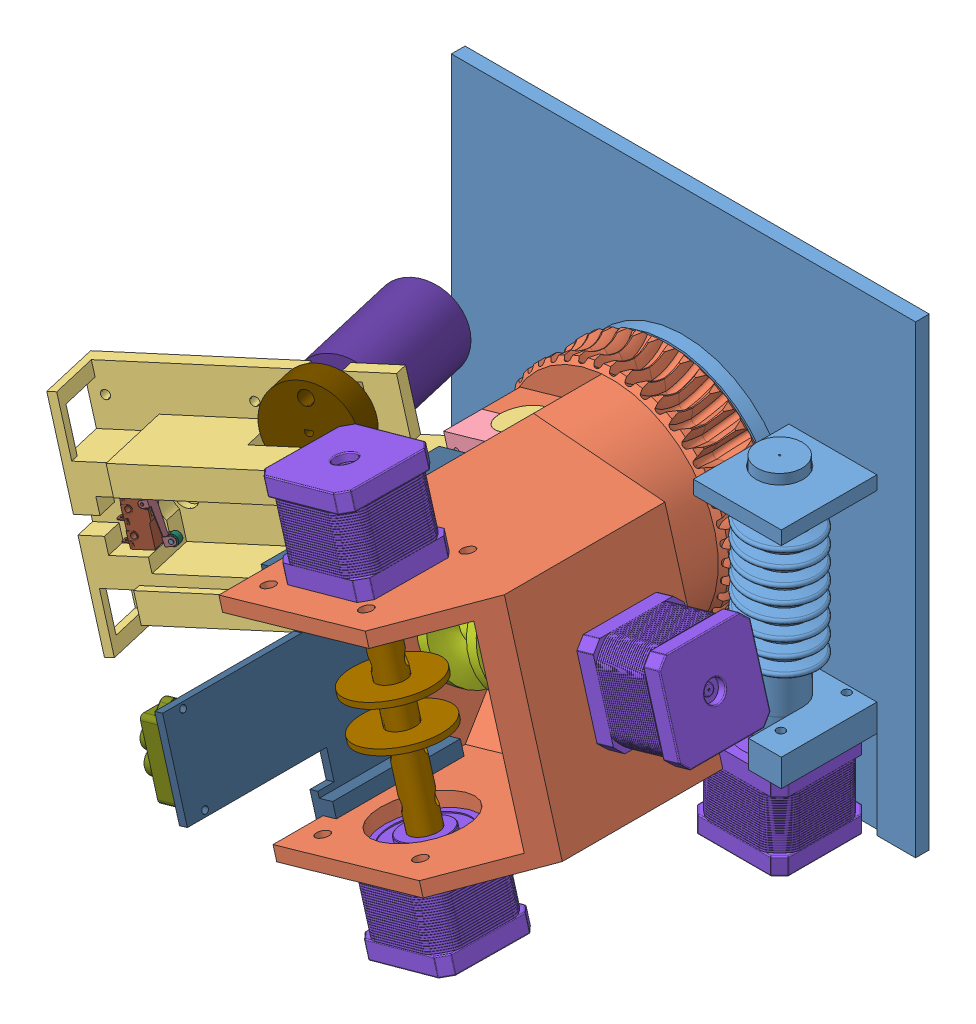
SolidWorks assembly AssemV5, configuration Default. Lengths in mm.
Overall size (330.56 216.84 251.9).
26 component instances, 19 part files, 48 mates.
Components (placement in the parent):
- StaticBaseV-2: StaticBaseV [Default] at (-73.3516 -55.0202 184.3743) size (215.9 215.9 50.8)
- EE183 - BaseV8-1: EE183 - BaseV8 [Varsayılan] at (34.5984 50.9073 210.6943) x (-0.27522 0.961381 0) z (0 0 -1) size (107.89 159.94 205.32)
- LaunchRailV9-1: LaunchRailV9 [Default] at (27.5196 31.2188 237.3254) x (-0.27522 0.961381 0) z (0.918082 0.262825 -0.29673) size (97.46 43.1 180.34)
- EE183B - RailConstraintV1-1: EE183B - RailConstraintV1 [Default] at (12.0372 6.9713 242.0943) x (0.961381 0.27522 0) z (-0.27522 0.961381 0) size (38.1 17.78 12.7)
- EE183B - RailConstraintV1-2: EE183B - RailConstraintV1 [Default] at (-4.2998 64.0387 242.0943) x (0.961381 0.27522 0) z (-0.27522 0.961381 0) size (38.1 17.78 12.7)
- EE183 - LaunchCartV5-1: EE183 - LaunchCartV5 [Default] at (3.8179 24.4336 248.0979) x (0.27522 -0.961381 0) z (-0.285271 -0.081666 -0.954961) size (45.72 40.64 34.29)
- EE183 - SolenoidV1-1: EE183 - SolenoidV1 [Default] at (32.5105 35.818 235.4411) x (-0.918082 -0.262825 0.29673) z (-0.27522 0.961381 0) size (54.73 25 26.63)
- EE183 - AugarV3-1: EE183 - AugarV3 [Default] at (252.3237 113.2278 316.3785) x (-0.114553 0.400148 -0.909263) z (0.961381 0.27522 0) size (38.1 38.1 90.17)
- Motor a Pasos Nema 17-1: Motor a Pasos Nema 17 [Predeterminado] at (52.3182 148.4565 366.0543) x (0.011317 0.00324 -0.999931) z (-0.961315 -0.275201 -0.011772) size (42.3 64.2 42.3)
- Motor a Pasos Nema 17-2: Motor a Pasos Nema 17 [Predeterminado] at (174.9581 91.0889 316.3893) x (-0.27522 0.961381 0) z (0 0 1) size (42.3 64.2 42.3)
- Motor a Pasos Nema 17-3: Motor a Pasos Nema 17 [Predeterminado] at (101.2552 -22.487 366.0543) x (0.961277 0.27519 0.014751) z (-0.014181 -0.00406 0.999891) size (42.3 64.2 42.3)
- EE183 - WindWheelV4-1: EE183 - WindWheelV4 [Default] at (90.246 15.9697 366.0543) x (0.694336 0.198772 0.691655) z (-0.27522 0.961381 0) size (38.1 38.1 95.81)
- EE183DB - SensorHolderV3-1: EE183DB - SensorHolderV3 [Default] at (17.9642 97.015 319.5643) x (0 0 -1) z (0.27522 -0.961381 0) size (148.46 25.62 97.79)
- Limit Switch-1: Limit Switch [Default] at (-126.03 11.7882 285.2276) x (0.27522 -0.961381 0) z (0.285271 0.081666 0.954961) size (19.88 22.22 6.9)
  - Body-1: Body [Default] at (-3.0926 15.7185 13.5391) size (19.88 14.3 6.9)
  - Switch_Button-1: Switch_Button [Default] at (3.7604 12.3412 16.7891) size (2 4 4)
  - Link-1: Link [Default] at (-1.7251 15.5431 16.7891) x (0.988221 0.153035 0) z (0 0 1) size (18.04 8.82 6.05)
  - Wheel shaft-1: Wheel shaft [Default] at (13.789 21.2849 14.2391) x (-0.16928 0.985568 0) z (0 0 1) size (1.82 1.82 5.1)
  - Wheel-1: Wheel [Default] at (13.789 21.2849 15.2941) x (0.999957 0.009288 0) z (0 0 1) size (4.67 4.67 2.99)
- mini_Lidar-1: mini_Lidar [Défaut] at (39.8186 52.9761 427.3873) x (0.27522 -0.961381 0) z (-0.961381 -0.27522 0) size (41.76 15 16)
- EE183 - MotorV2-1: EE183 - MotorV2 [Default] at (-40.447 -5.4116 262.0911) x (-0.936617 -0.187685 0.295842) z (-0.285271 -0.081666 -0.954961) size (36.6 36.6 64.52)
- EE183 - MotorV2-2: EE183 - MotorV2 [Default] at (-58.8812 58.9815 262.0911) x (-0.936617 -0.187685 0.295842) z (-0.285271 -0.081666 -0.954961) size (36.6 36.6 64.52)
- EE183 - WheelV1-1: EE183 - WheelV1 [Default] at (-54.896 60.1224 275.4319) x (-0.946187 -0.134858 0.294183) z (-0.285271 -0.081666 -0.954961) size (38.1 38.1 19.05)
- EE183 - WheelV1-2: EE183 - WheelV1 [Default] at (-36.4618 -4.2707 275.4319) x (-0.720576 0.675249 0.157508) z (-0.285271 -0.081666 -0.954961) size (38.1 38.1 19.05)
- EE183 - WormGearV2-1: EE183 - WormGearV2 [Varsayılan] at (91.0536 52.0794 204.9983) x (0 1 0) z (-0.546944 0 0.837169) size (108.6 34.9 36.7)
- Motor a Pasos Nema 17-4: Motor a Pasos Nema 17 [Predeterminado] at (98.3792 -55.9586 209.7858) size (42.3 64.2 42.3)
Mates (geometry in assembly coordinates):
- Concentric2: concentric: circle of StaticBaseV-2; cylinder of EE183 - BaseV8-1 through (34.5984 50.9073 209.7743) axis (0 0 -1) radius 38.862
- Coincident2: coincident: plane of StaticBaseV-2 through (-73.3516 -55.0202 209.7743) normal (0 0 1); plane of EE183 - BaseV8-1 through (34.5984 50.9073 209.7743) normal (0 0 -1)
- Concentric3: concentric: cylinder of EE183 - BaseV8-1 through (35.2819 -5.0083 242.0943) axis (-0.27522 0.961381 0) radius 10.16; cylinder of LaunchRailV9-1 through (30.3515 12.2143 242.0943) axis (-0.27522 0.961381 0) radius 10.16
- Coincident3: coincident: plane of EE183 - BaseV8-1 through (-7.7951 76.2482 242.0943) normal (-0.27522 0.961381 0); circle of LaunchRailV9-1
- Concentric4: concentric: cylinder of EE183 - BaseV8-1 through (-1.7741 71.3668 197.0743) axis (0 0 1) radius 1.143; cylinder of EE183B - RailConstraintV1-2 through (-1.7741 71.3668 259.8743) axis (0 0 -1) radius 1.143
- Coincident4: coincident: cylinder of EE183 - BaseV8-1 through (26.3078 79.406 197.0743) axis (0 0 1) radius 1.143; circle of EE183B - RailConstraintV1-2
- Coincident5: coincident: plane of EE183 - BaseV8-1 through (34.5984 50.9073 242.0943) normal (0 0 1); plane of EE183B - RailConstraintV1-2 through (-7.7951 76.2482 242.0943) normal (0 0 -1)
- Concentric5: concentric: cylinder of EE183 - BaseV8-1 through (42.6448 22.3386 197.0743) axis (0 0 1) radius 1.143; cylinder of EE183B - RailConstraintV1-1 through (42.6448 22.3386 259.8743) axis (0 0 -1) radius 1.143
- Concentric6: concentric: cylinder of EE183 - BaseV8-1 through (14.5629 14.2994 197.0743) axis (0 0 1) radius 1.143; cylinder of EE183B - RailConstraintV1-1 through (14.5629 14.2994 259.8743) axis (0 0 -1) radius 1.143
- Coincident6: coincident: plane of EE183 - BaseV8-1 through (34.5984 50.9073 242.0943) normal (0 0 1); plane of EE183B - RailConstraintV1-1 through (8.5419 19.1808 242.0943) normal (0 0 -1)
- Coincident10: coincident: plane of LaunchRailV9-1 through (-161.5192 12.4255 320.5914) normal (0.285271 0.081666 0.954961); plane of EE183 - LaunchCartV5-1 through (-27.4788 15.4741 280.2895) normal (-0.285271 -0.081666 -0.954961)
- Coincident11: coincident: plane of LaunchRailV9-1 through (-161.5192 12.4255 320.5914) normal (0.285271 0.081666 0.954961); plane of EE183 - LaunchCartV5-1 through (-27.4788 15.4741 280.2895) normal (-0.285271 -0.081666 -0.954961)
- Coincident12: coincident: plane of LaunchRailV9-1 through (-159.0347 -22.1872 297.621) normal (-0.27522 0.961381 0); plane of EE183 - LaunchCartV5-1 through (-33.4929 13.7524 260.157) normal (0.27522 -0.961381 0)
- Coincident13: coincident: plane of LaunchRailV9-1 through (38.3343 41.4086 258.4116) normal (-0.918082 -0.262825 0.29673); plane of EE183 - SolenoidV1-1 through (25.1809 61.4214 235.4411) normal (0.918082 0.262825 -0.29673)
- Coincident14: coincident: plane of LaunchRailV9-1 through (-159.0347 -22.1872 297.621) normal (0.285271 0.081666 0.954961); plane of EE183 - SolenoidV1-1 through (25.1809 61.4214 235.4411) normal (-0.285271 -0.081666 -0.954961)
- Coincident15: coincident: plane of LaunchRailV9-1 through (11.8822 57.6143 212.3228) normal (0.27522 -0.961381 0); plane of EE183 - SolenoidV1-1 through (25.1809 61.4214 235.4411) normal (-0.27522 0.961381 0)
- Coincident16: coincident: plane of EE183 - LaunchCartV5-1 through (3.8179 24.4336 248.0979) normal (0.918082 0.262825 -0.29673); circle of EE183 - SolenoidV1-1
- Concentric7: concentric: cylinder of EE183 - BaseV8-1 through (-17.2626 36.0607 316.3893) axis (0.961381 0.27522 0) radius 17; cylinder of Motor a Pasos Nema 17-2 through (113.2375 73.4197 316.3893) axis (0.961381 0.27522 0) radius 2.5
- Coincident17: coincident: plane of EE183 - BaseV8-1 through (136.5029 80.0801 344.9643) normal (0.961381 0.27522 0); plane of Motor a Pasos Nema 17-2 through (136.5029 80.0801 316.3893) normal (-0.961381 -0.27522 0)
- Concentric8: concentric: cylinder of EE183 - AugarV3-1 through (201.7326 98.7538 316.3893) axis (-0.961381 -0.27522 0) radius 4.7625; cylinder of Motor a Pasos Nema 17-2 through (113.2375 73.4197 316.3893) axis (0.961381 0.27522 0) radius 2.5
- Coincident18: coincident: plane of EE183 - AugarV3-1 through (134.3142 80.4587 317.4416) normal (0.961381 0.27522 0); plane of Motor a Pasos Nema 17-2 through (134.5801 79.5296 316.3893) normal (-0.961381 -0.27522 0)
- Concentric9: concentric: cylinder of EE183 - BaseV8-1 through (61.9402 114.8457 366.0543) axis (0.27522 -0.961381 0) radius 20; cylinder of Motor a Pasos Nema 17-1 through (69.9873 86.7359 366.0543) axis (-0.27522 0.961381 0) radius 2.5
- Coincident19: coincident: plane of EE183 - BaseV8-1 through (21.1387 97.9238 344.9643) normal (-0.27522 0.961381 0); plane of Motor a Pasos Nema 17-1 through (63.327 110.0013 366.0543) normal (0.27522 -0.961381 0)
- Concentric10: concentric: cylinder of EE183 - BaseV8-1 through (61.9402 114.8457 366.0543) axis (0.27522 -0.961381 0) radius 20; cylinder of Motor a Pasos Nema 17-3 through (83.5861 39.2337 366.0543) axis (0.27522 -0.961381 0) radius 2.5
- Coincident20: coincident: plane of EE183 - BaseV8-1 through (48.0581 3.8907 344.9643) normal (0.27522 -0.961381 0); plane of Motor a Pasos Nema 17-3 through (90.2464 15.9682 366.0543) normal (-0.27522 0.961381 0)
- Concentric11: concentric: cylinder of Motor a Pasos Nema 17-1 through (69.9873 86.7359 366.0543) axis (-0.27522 0.961381 0) radius 2.5; cylinder of EE183 - WindWheelV4-1 through (63.8774 108.0785 366.0543) axis (0.27522 -0.961381 0) radius 6.35
- Coincident21: coincident: plane of Motor a Pasos Nema 17-1 through (63.8774 108.0785 366.0543) normal (0.27522 -0.961381 0); plane of EE183 - WindWheelV4-1 through (63.8774 108.0785 366.0543) normal (-0.27522 0.961381 0)
- Coincident22: coincident: plane of EE183 - BaseV8-1 through (34.5984 50.9073 344.9643) normal (0 0 1); plane of EE183DB - SensorHolderV3-1 through (66.0094 22.2611 344.9643) normal (0 0 -1)
- Coincident23: coincident: plane of EE183 - BaseV8-1 through (43.6335 53.4938 287.8143) normal (-0.961381 -0.27522 0); plane of EE183DB - SensorHolderV3-1 through (31.9214 94.4055 319.5643) normal (0.961381 0.27522 0)
- Coincident24: coincident: plane of EE183 - BaseV8-1 through (21.1387 97.9238 344.9643) normal (-0.27522 0.961381 0); plane of EE183DB - SensorHolderV3-1 through (17.9642 97.015 319.5643) normal (-0.27522 0.961381 0)
- Concentric12: concentric: cylinder of LaunchRailV9-1 through (-120.0759 11.4098 276.4604) axis (0.285271 0.081666 0.954961) radius 1.143; cylinder of Limit Switch-1/Body-1 through (-115.2994 12.7772 292.45) axis (0.285271 0.081666 0.954961) radius 1.225
- Coincident25: coincident: plane of LaunchRailV9-1 through (-110.2016 20.5114 293.9309) normal (0.285271 0.081666 0.954961); plane of Limit Switch-1/Body-1 through (-104.1816 0.9971 293.8014) normal (-0.285271 -0.081666 -0.954961)
- Parallel2: parallel: plane of LaunchRailV9-1 through (-101.3612 0.5849 303.6333) normal (-0.27522 0.961381 0); line of Limit Switch-1/Body-1 through (-110.4891 -1.2246 302.6821) axis (0.918082 0.262825 -0.29673)
- Concentric15: concentric: circle of EE183DB - SensorHolderV3-1; cylinder of mini_Lidar-1 through (30.0578 68.9048 427.3873) axis (0.961381 0.27522 0) radius 0.5875
- Parallel3: parallel: plane of EE183DB - SensorHolderV3-1 through (17.9642 97.015 436.2773) normal (0 0 1); plane of mini_Lidar-1 through (25.2528 63.8887 434.8873) normal (0 0 1)
- Coincident28: coincident: plane of EE183DB - SensorHolderV3-1 through (27.5595 95.7989 294.1643) normal (-0.961381 -0.27522 0); plane of mini_Lidar-1 through (35.8279 66.9161 421.8873) normal (0.961381 0.27522 0)
- Concentric16: concentric: cylinder of LaunchRailV9-1 through (-67.2033 56.5991 234.2324) axis (0.285271 0.081666 0.954961) radius 7.62; cylinder of EE183 - MotorV2-2 through (-77.2869 53.7124 200.477) axis (0.285271 0.081666 0.954961) radius 18.3
- Coincident29: coincident: plane of LaunchRailV9-1 through (-171.9402 16.0473 291.5569) normal (-0.285271 -0.081666 -0.954961); plane of EE183 - MotorV2-2 through (-61.055 58.3592 254.8143) normal (0.285271 0.081666 0.954961)
- Concentric17: concentric: cylinder of LaunchRailV9-1 through (-48.7691 -7.794 234.2324) axis (0.285271 0.081666 0.954961) radius 7.62; cylinder of EE183 - MotorV2-1 through (-58.8527 -10.6807 200.477) axis (0.285271 0.081666 0.954961) radius 18.3
- Coincident30: coincident: plane of LaunchRailV9-1 through (-171.9402 16.0473 291.5569) normal (-0.285271 -0.081666 -0.954961); plane of EE183 - MotorV2-1 through (-42.6208 -6.0339 254.8143) normal (0.285271 0.081666 0.954961)
- Concentric18: concentric: cylinder of EE183 - MotorV2-2 through (-61.055 58.3592 254.8143) axis (0.285271 0.081666 0.954961) radius 1.5875; cylinder of EE183 - WheelV1-1 through (-60.3304 58.5666 257.2399) axis (0.285271 0.081666 0.954961) radius 6.35
- Distance1: distance = 2.54 mm: plane of EE183 - WheelV1-1 through (-60.3304 58.5666 257.2399) normal (-0.285271 -0.081666 -0.954961); plane of EE183 - MotorV2-2 through (-61.055 58.3592 254.8143) normal (0.285271 0.081666 0.954961)
- Concentric19: concentric: cylinder of EE183 - MotorV2-1 through (-58.8527 -10.6807 200.477) axis (0.285271 0.081666 0.954961) radius 18.3; cylinder of EE183 - WheelV1-2 through (-41.8962 -5.8265 257.2399) axis (0.285271 0.081666 0.954961) radius 6.35
- Distance2: distance = 2.54 mm: plane of EE183 - MotorV2-1 through (-42.6208 -6.0339 254.8143) normal (0.285271 0.081666 0.954961); plane of EE183 - WheelV1-2 through (-41.8962 -5.8265 257.2399) normal (-0.285271 -0.081666 -0.954961)
- Concentric20: concentric: cylinder of StaticBaseV-2 through (98.3792 160.8798 209.7858) axis (0 -1 0) radius 10.922; cylinder of EE183 - WormGearV2-1 through (98.3792 94.6424 209.7858) axis (0 -1 0) radius 10.4775
- Coincident35: coincident: plane of StaticBaseV-2 through (100.9178 -13.9586 235.1743) normal (0 -1 0); plane of EE183 - WormGearV2-1 through (98.3792 -13.9586 209.7858) normal (0 -1 0)
- Concentric21: concentric: cylinder of EE183 - WormGearV2-1 through (98.3792 -13.9586 209.7858) axis (0 1 0) radius 10.4775; cylinder of Motor a Pasos Nema 17-4 through (98.3792 8.2414 209.7858) axis (0 -1 0) radius 2.5
- Coincident36: coincident: plane of StaticBaseV-2 through (100.9178 -13.9586 235.1743) normal (0 -1 0); plane of Motor a Pasos Nema 17-4 through (98.3792 -13.9586 209.7858) normal (0 1 0)
